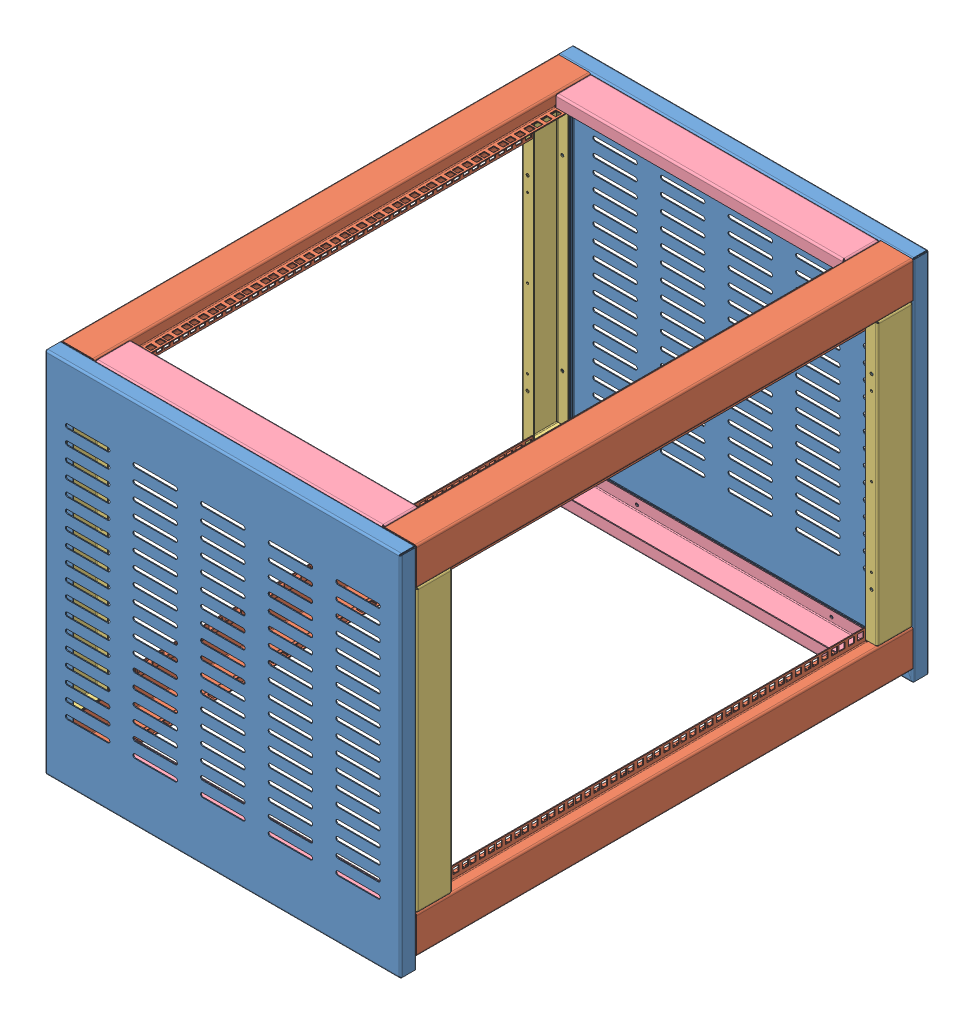
SolidWorks assembly 19inch Rack 16U, configuration Default. Lengths in mm.
Overall size (600.67 620.33 891.02).
14 component instances, 4 part files, 0 mates.
Components (placement in the parent):
- 19inch Rack Top-1: 19inch Rack Top [Default] at (0 21.4558 0) size (600.67 620.33 27.35)
- 19inch Rack Corner Section x 16U-1: 19inch Rack Corner Section x 16U [Default] at (300 331.4558 445.5) x (0 1 0) z (0 0 1) size (82.85 75 837)
- 19inch Rack Corner Section x 16U-2: 19inch Rack Corner Section x 16U [Default] at (300 -268.5442 445.5) x (0 -1 0) z (0 0 -1) size (82.85 75 837)
- 19inch Rack In Fill section Side-1: 19inch Rack In Fill section Side [Default] at (300 31.4558 57) x (0 1 0) z (1 0 0) size (475.02 60.02 20.01)
- 19inch Rack In Fill section Side-2: 19inch Rack In Fill section Side [Default] at (300 31.4558 834) x (0 -1 0) z (1 0 0) size (475.02 60.02 20.01)
- 19inch Rack In Fill section Front-Rear-1: 19inch Rack In Fill section Front-Rear [Default] at (0 331.4558 57) x (1 0 0) z (0 1 0) size (487.02 60.02 20.01)
- 19inch Rack In Fill section Front-Rear-2: 19inch Rack In Fill section Front-Rear [Default] at (0 -268.5442 834) x (1 0 0) z (0 -1 0) size (487.02 60.02 20.01)
- 19inch Rack In Fill section Front-Rear-3: 19inch Rack In Fill section Front-Rear [Default] at (0 331.4558 834) x (-1 0 0) z (0 1 0) size (487.02 60.02 20.01)
- 19inch Rack In Fill section Front-Rear-4: 19inch Rack In Fill section Front-Rear [Default] at (0 -268.5442 57) x (-1 0 0) z (0 -1 0) size (487.02 60.02 20.01)
- 19inch Rack Corner Section x 16U-3: 19inch Rack Corner Section x 16U [Default] at (-300 -268.5442 445.5) x (0 -1 0) z (0 0 1) size (82.85 75 837)
- 19inch Rack Corner Section x 16U-4: 19inch Rack Corner Section x 16U [Default] at (-300 331.4558 445.5) x (0 1 0) z (0 0 -1) size (82.85 75 837)
- 19inch Rack In Fill section Side-3: 19inch Rack In Fill section Side [Default] at (-300 31.4558 834) x (0 1 0) z (-1 0 0) size (475.02 60.02 20.01)
- 19inch Rack In Fill section Side-4: 19inch Rack In Fill section Side [Default] at (-300 31.4558 57) x (0 -1 0) z (-1 0 0) size (475.02 60.02 20.01)
- 19inch Rack Top-2: 19inch Rack Top [Default] at (0 21.4558 891) x (-1 0 0) z (0 0 -1) size (600.67 620.33 27.35)
